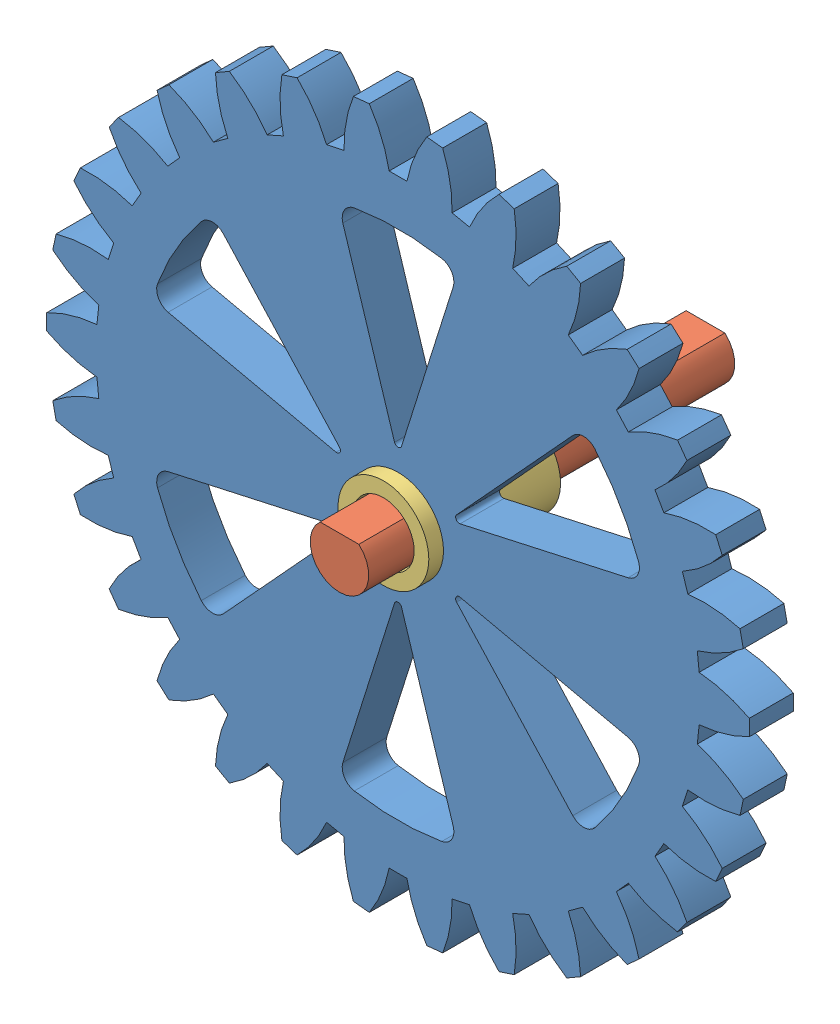
SolidWorks assembly third subassembly, configuration Default. Lengths in mm.
Overall size (48 47.84 25).
4 component instances, 3 part files, 7 mates.
Components (placement in the parent):
- root_gear copy-1: root_gear copy [30T 1.5Mod] at (9.2311 21.7899 21.0363) size (48 47.84 3)
- axle-1: axle [25 mm tall] at (9.2311 21.7899 3.0363) size (4 3.5 25)
- spacer-1: spacer [4.2 mm ID] at (9.2311 21.7899 24.0363) size (6.2 6.2 1)
- spacer-2: spacer [5mm tall] at (9.2311 21.7899 16.0363) x (0.014596 -0.999893 0) z (0 0 1) size (6.2 6.2 5)
Mates (geometry in assembly coordinates):
- Concentric1: concentric anti-aligned: cylinder of root_gear copy-1 through (9.2311 21.7899 14.0363) axis (0 0 1) radius 2; cylinder of axle-1 through (9.2311 21.7899 28.0363) axis (0 0 -1) radius 2
- Parallel1: parallel: line of root_gear copy-1 through (10.5539 23.2899 24.0363) axis (-1 0 0); plane of axle-1 through (7.9082 23.2899 28.0363) normal (0 1 0)
- Concentric2: concentric aligned: cylinder of axle-1 through (9.2311 21.7899 28.0363) axis (0 0 -1) radius 2; cylinder of spacer-1 through (9.2311 21.7899 25.0363) axis (0 0 -1) radius 2.1
- Concentric3: concentric aligned: cylinder of axle-1 through (9.2311 21.7899 28.0363) axis (0 0 -1) radius 2; cylinder of spacer-2 through (9.2311 21.7899 21.0363) axis (0 0 -1) radius 2.1
- Coincident2: coincident anti-aligned: plane of root_gear copy-1 through (9.2311 21.7899 24.0363) normal (0 0 1); plane of spacer-1 through (9.2311 21.7899 24.0363) normal (0 0 -1)
- Coincident3: coincident anti-aligned: plane of root_gear copy-1 through (9.2311 21.7899 21.0363) normal (0 0 -1); plane of spacer-2 through (9.2311 21.7899 21.0363) normal (0 0 1)
- Distance1: distance = 3 mm aligned: plane of spacer-1 through (9.2311 21.7899 25.0363) normal (0 0 1); plane of axle-1 through (9.2311 21.7899 28.0363) normal (0 0 1)
